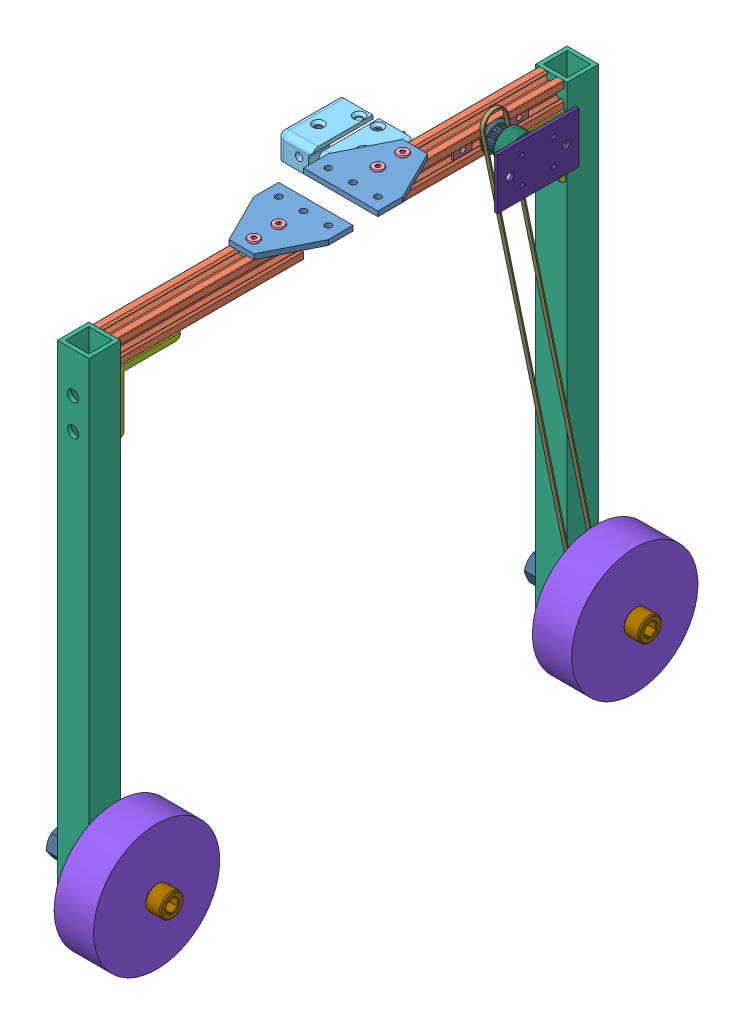
SolidWorks assembly FRP Leg SubAssembly, configuration Default. Lengths in mm.
Overall size (138.8 429.85 487).
31 component instances, 17 part files, 49 mates.
Components (placement in the parent):
- Joining Plate T-1: Joining Plate T [Default] at origin size (60 4 60)
- V-Slot 20x20x150Linear Rail-1: V-Slot 20x20x150Linear Rail [Default] at (0 -10 -160) size (20 20 150)
- Double Tee Nut-1: Double Tee Nut [Default] at (5 -3.4 -11.56) x (0 0 -1) z (0 1 0) size (36.88 10 3)
- Low Profile Screw M5-1: Low Profile Screw M5 [M5 x 8] at (0 -4 -20) x (0 -1 0) z (0 0 1) size (9.62 9 9)
- Low Profile Screw M5-2: Low Profile Screw M5 [M5 x 8] at (0 -4 -40) x (0 -1 0) z (-0.926384 0 0.37658) size (9.62 9 9)
- Low Profile Screw M5-8: Low Profile Screw M5 [M5 x 8] at (0 -4 80) x (0 -1 0) z (0.926384 0 0.37658) size (9.62 9 9)
- Low Profile Screw M5-10: Low Profile Screw M5 [M5 x 8] at (0 -4 60) x (0 -1 0) z (0 0 1) size (9.62 9 9)
- V-Slot 20x20x150Linear Rail-4: V-Slot 20x20x150Linear Rail [Default] at (0 -10 50) size (20 20 150)
- Joining Plate T-4: Joining Plate T [Default] at (0 0 40) x (-1 0 0) z (0 0 -1) size (60 4 60)
- Double Tee Nut-3: Double Tee Nut [Default] at (5 -3.4 88.44) x (0 0 -1) z (0 1 0) size (36.88 10 3)
- Limit Switch Mount_Larger-1: Limit Switch Mount_Larger [Default] at (-28 -8 -42) x (0 0 -1) z (1 0 0) size (56 20 61.19)
- FRP Leg-1: FRP Leg [Default] at (-0.25 -381 -172.7) x (0 0 -1) z (1 0 0) size (25.4 381 25.4)
- L-bracket 20x20-1: L-bracket 20x20 [Default] at (11 -20 -160) x (0 -1 0) z (-1 0 0) size (50 50 22.5)
- Plastic Wheel-1: Plastic Wheel [Default] at (22.61 -361 -172.7) x (0 0 -1) z (1 0 0) size (101.6 101.6 31.75)
- .5in_NYLON SOCKET HEAD CAP SCREW-2: .5in_NYLON SOCKET HEAD CAP SCREW [95868A439] at (-21.84 -361 -172.7) x (0 -0.037736 0.999288) z (-1 0 0) size (19.05 19.05 91.16)
- 94812A620_NYLON 6-6 HEX NUT-1: 94812A620_NYLON 6-6 HEX NUT [94812A620] at (-18.8873 -361 -172.7) x (0 0.381849 -0.924225) z (0 -0.924225 -0.381849) size (19.45 12.65 22.46)
- 1254N220_MXL SERIES LIGHTWEIGHT TIMING BELT PULLEY - Modified-1: 1254N220_MXL SERIES LIGHTWEIGHT TIMING BELT PULLEY - Modified [1254N22] at (13.8724 -361 -172.7) size (11.13 22.35 22.35)
- Pulley-1: Pulley [Default] at (18.6034 -361 -172.7) x (0 -0.202541 0.979274) z (-1 0 0) size (20 395 3.17)
- Tee Nut-12: Tee Nut [Default] at (6.6 -9.5 -103.0192) x (0 0 -1) z (1 0 0) size (15 10 3)
- 1254N220_MXL SERIES LIGHTWEIGHT TIMING BELT PULLEY-3: 1254N220_MXL SERIES LIGHTWEIGHT TIMING BELT PULLEY [1254N22] at (19.7376 -9.5 -103.0192) x (-1 0 0) z (0 -0.692344 -0.721567) size (17.48 22.35 22.35)
- Low Profile Screw M5-11: Low Profile Screw M5 [M5 x 25] at (3.9 -9.5 -103.0192) x (-1 0 0) z (0 -0.155719 -0.987801) size (26.62 9 9)
- Encoder Magnet Mount-1: Encoder Magnet Mount [Default] at (30.6252 -9.5 -103.0192) x (0 0 1) z (-1 0 0) size (24 24 11.5)
- Encoder Board-1: Encoder Board [Default] at (41.6252 -9.5 -103.0192) x (0 0 -1) z (1 0 0) size (31.5 27 3.1)
- Encoder Board Mount-1: Encoder Board Mount [Default] at (46.1252 -9.5 -103.0192) x (0 0 1) z (-1 0 0) size (65.5 41 2.5)
- Tee Nut-13: Tee Nut [Default] at (8.2 -9.5 -125.7692) x (0 0 -1) z (-1 0 0) size (15 10 3)
- Tee Nut-14: Tee Nut [Default] at (8.2 -9.5 -80.2692) x (0 0 -1) z (-1 0 0) size (15 10 3)
- FRP Leg-2: FRP Leg [Default] at (-0.25 -381 212.7) x (0 0 1) z (-1 0 0) size (25.4 381 25.4)
- Plastic Wheel-2: Plastic Wheel [Default] at (54.36 -361 212.7) x (0 0 1) z (-1 0 0) size (101.6 101.6 31.75)
- .5in_NYLON SOCKET HEAD CAP SCREW-3: .5in_NYLON SOCKET HEAD CAP SCREW [95868A439] at (-21.84 -361 212.7) x (0 0.037736 0.999288) z (-1 0 0) size (19.05 19.05 91.16)
- 94812A620_NYLON 6-6 HEX NUT-2: 94812A620_NYLON 6-6 HEX NUT [94812A620] at (-18.8873 -361 212.7) x (0 -0.381849 -0.924225) z (0 -0.924225 0.381849) size (19.45 12.65 22.46)
- L-bracket 20x20-2: L-bracket 20x20 [Default] at (-11.5 -20 200) x (0 -1 0) z (1 0 0) size (50 50 22.5)
Mates (geometry in assembly coordinates):
- Coincident1: coincident anti-aligned: plane of Joining Plate T-1 through (0 0 0) normal (0 -1 0); plane of V-Slot 20x20x150Linear Rail-1 through (0 0 -10) normal (0 1 0)
- Coincident2: coincident: point of Joining Plate T-1; plane of V-Slot 20x20x150Linear Rail-1 through (10 -10 -10) normal (1 0 0)
- Distance1: distance = 20 mm aligned: plane of Joining Plate T-1 through (30 4 10) normal (0 0 1); plane of V-Slot 20x20x150Linear Rail-1 through (0 -10 -10) normal (0 0 1)
- Coincident36: coincident anti-aligned: plane of V-Slot 20x20x150Linear Rail-1 through (0 -1.8 -10) normal (0 -1 0); plane of Double Tee Nut-1 through (-3.5 -1.8 -46.94) normal (0 1 0)
- Concentric11: concentric anti-aligned: cylinder of Joining Plate T-1 through (0 4 -20) axis (0 -1 0) radius 2.55; cylinder of Double Tee Nut-1 through (0 -0.4 -20) axis (0 1 0) radius 2.1
- Concentric12: concentric anti-aligned: cylinder of Joining Plate T-1 through (0 4 -40) axis (0 -1 0) radius 2.55; cylinder of Double Tee Nut-1 through (0 -0.4 -40) axis (0 1 0) radius 2.1
- Coincident49: coincident anti-aligned: plane of Joining Plate T-1 through (0 4 0) normal (0 1 0); plane of Low Profile Screw M5-1 through (4.1614 4 -20) normal (0 -1 0)
- Concentric22: concentric aligned: cylinder of Joining Plate T-1 through (0 4 -20) axis (0 -1 0) radius 2.55; cylinder of Low Profile Screw M5-1 through (0 4 -20) axis (0 -1 0) radius 2.5
- Concentric23: concentric aligned: cylinder of Joining Plate T-1 through (0 4 -40) axis (0 -1 0) radius 2.55; cylinder of Low Profile Screw M5-2 through (0 4 -40) axis (0 -1 0) radius 2.5
- Concentric24: concentric aligned: cylinder of Joining Plate T-1 through (0 4 -40) axis (0 -1 0) radius 2.55; cylinder of Low Profile Screw M5-2 through (0 4 -40) axis (0 -1 0) radius 2.5
- Coincident50: coincident anti-aligned: plane of Joining Plate T-1 through (0 4 0) normal (0 1 0); plane of Low Profile Screw M5-2 through (1.5671 4 -36.1449) normal (0 -1 0)
- Coincident54: coincident anti-aligned: plane of V-Slot 20x20x150Linear Rail-1 through (-10 -10 -10) normal (-1 0 0); plane of Limit Switch Mount_Larger-1 through (-10 0 -42) normal (1 0 0)
- Coincident55: coincident aligned: plane of V-Slot 20x20x150Linear Rail-1 through (0 -10 -10) normal (0 0 1); plane of Limit Switch Mount_Larger-1 through (-28 0 -10) normal (0 0 1)
- Coincident57: coincident aligned: plane of V-Slot 20x20x150Linear Rail-1 through (0 0 -10) normal (0 1 0); plane of Limit Switch Mount_Larger-1 through (-28 0 -42) normal (0 1 0)
- Coincident58: coincident aligned: plane of V-Slot 20x20x150Linear Rail-1 through (0 -10 -160) normal (0 0 -1); plane of L-bracket 20x20-1 through (-11.5 -20 -160) normal (0 0 -1)
- Coincident59: coincident anti-aligned: plane of V-Slot 20x20x150Linear Rail-1 through (0 -20 -10) normal (0 -1 0); plane of L-bracket 20x20-1 through (-11.5 -20 -110) normal (0 1 0)
- Distance2: distance = 1 mm aligned: plane of L-bracket 20x20-1 through (11 -20 -160) normal (1 0 0); plane of V-Slot 20x20x150Linear Rail-1 through (10 -10 -10) normal (1 0 0)
- Concentric25: concentric anti-aligned: cylinder of FRP Leg-1 through (-0.25 -32.5 -185.4) axis (0 0 1) radius 4.5392; cylinder of L-bracket 20x20-1 through (-0.25 -32.5 -110) axis (0 0 -1) radius 3.6
- Coincident62: coincident anti-aligned: plane of FRP Leg-1 through (-12.95 0 -160) normal (0 0 1); plane of L-bracket 20x20-1 through (-11.5 -20 -160) normal (0 0 -1)
- Concentric26: concentric anti-aligned: cylinder of FRP Leg-1 through (-0.25 -57.5 -185.4) axis (0 0 1) radius 4.5392; cylinder of L-bracket 20x20-1 through (-0.25 -57.5 -110) axis (0 0 -1) radius 3.6
- Distance3: distance = 10.16 mm anti-aligned: plane of FRP Leg-1 through (12.45 0 -160) normal (1 0 0); plane of Plastic Wheel-1 through (22.61 -361 -172.7) normal (-1 0 0)
- Concentric32: concentric aligned: cylinder of FRP Leg-1 through (12.45 -361 -172.7) axis (-1 0 0) radius 2.5; cylinder of Plastic Wheel-1 through (54.36 -361 -172.7) axis (-1 0 0) radius 6.35
- Concentric33: concentric aligned: cylinder of Plastic Wheel-1 through (54.36 -361 -172.7) axis (-1 0 0) radius 6.35; cylinder of .5in_NYLON SOCKET HEAD CAP SCREW-2 through (54.36 -361 -172.7) axis (-1 0 0) radius 6.35
- Coincident68: coincident anti-aligned: plane of Plastic Wheel-1 through (54.36 -361 -172.7) normal (1 0 0); plane of .5in_NYLON SOCKET HEAD CAP SCREW-2 through (54.36 -361 -172.7) normal (-1 0 0)
- Coincident69: coincident anti-aligned: plane of FRP Leg-1 through (-12.95 0 -160) normal (-1 0 0); plane of 94812A620_NYLON 6-6 HEX NUT-1 through (-12.95 -361 -172.7) normal (1 0 0)
- Concentric34: concentric anti-aligned: circle of .5in_NYLON SOCKET HEAD CAP SCREW-2; circle of 94812A620_NYLON 6-6 HEX NUT-1
- Coincident70: coincident anti-aligned: plane of Plastic Wheel-1 through (22.61 -361 -172.7) normal (-1 0 0); plane of 1254N220_MXL SERIES LIGHTWEIGHT TIMING BELT PULLEY - Modified-1 through (22.61 -372.176 -172.7) normal (1 0 0)
- Concentric36: concentric aligned: cylinder of .5in_NYLON SOCKET HEAD CAP SCREW-2 through (54.36 -361 -172.7) axis (-1 0 0) radius 6.35; cylinder of 1254N220_MXL SERIES LIGHTWEIGHT TIMING BELT PULLEY - Modified-1 through (22.61 -361 -172.7) axis (-1 0 0) radius 6.35
- Concentric37: concentric anti-aligned: circle of 1254N220_MXL SERIES LIGHTWEIGHT TIMING BELT PULLEY - Modified-1; cylinder of Pulley-1 through (15.4284 -361 -172.7) axis (1 0 0) radius 9
- Distance4: distance = 2 mm anti-aligned: plane of 1254N220_MXL SERIES LIGHTWEIGHT TIMING BELT PULLEY - Modified-1 through (20.6034 -370.0551 -172.7) normal (-1 0 0); plane of Pulley-1 through (18.6034 -361 -172.7) normal (1 0 0)
- Coincident74: coincident anti-aligned: plane of V-Slot 20x20x150Linear Rail-1 through (8.2 -10 -10) normal (-1 0 0); plane of Tee Nut-12 through (8.2 -6.5 -109.0192) normal (1 0 0)
- Coincident75: coincident anti-aligned: plane of V-Slot 20x20x150Linear Rail-1 through (0 -4.5 -10) normal (0 -1 0); plane of Tee Nut-12 through (8.2 -4.5 -100.0192) normal (0 1 0)
- Concentric40: concentric aligned: cylinder of Tee Nut-12 through (9.6 -9.5 -103.0192) axis (1 0 0) radius 2.1; cylinder of 1254N220_MXL SERIES LIGHTWEIGHT TIMING BELT PULLEY-3 through (28.4752 -9.5 -103.0192) axis (1 0 0) radius 3.175
- Concentric41: concentric anti-aligned: cylinder of 1254N220_MXL SERIES LIGHTWEIGHT TIMING BELT PULLEY-3 through (28.4752 -9.5 -103.0192) axis (1 0 0) radius 3.175; cylinder of Low Profile Screw M5-11 through (28.9 -9.5 -103.0192) axis (-1 0 0) radius 2.5
- Coincident76: coincident anti-aligned: plane of V-Slot 20x20x150Linear Rail-1 through (3.9 -10 -10) normal (1 0 0); plane of Low Profile Screw M5-11 through (3.9 -9.5 -103.0192) normal (-1 0 0)
- Distance5: distance = 1 mm anti-aligned: plane of 1254N220_MXL SERIES LIGHTWEIGHT TIMING BELT PULLEY-3 through (11 -17.5642 -95.2815) normal (-1 0 0); plane of V-Slot 20x20x150Linear Rail-1 through (10 -10 -10) normal (1 0 0)
- Coincident78: coincident anti-aligned: plane of 1254N220_MXL SERIES LIGHTWEIGHT TIMING BELT PULLEY-3 through (22.1252 -17.5642 -95.2815) normal (1 0 0); plane of Encoder Magnet Mount-1 through (22.1252 -9.5 -103.0192) normal (-1 0 0)
- Concentric42: concentric aligned: cylinder of 1254N220_MXL SERIES LIGHTWEIGHT TIMING BELT PULLEY-3 through (28.4752 -9.5 -103.0192) axis (1 0 0) radius 8.7376; cylinder of Encoder Magnet Mount-1 through (22.1252 -9.5 -103.0192) axis (1 0 0) radius 12
- Distance6: distance = 10 mm anti-aligned: plane of Encoder Board Mount-1 through (43.6252 -9.5 -103.0192) normal (-1 0 0); plane of Encoder Magnet Mount-1 through (33.6252 -9.5 -103.0192) normal (1 0 0)
- Coincident80: coincident anti-aligned: plane of Encoder Board-1 through (43.6252 -9.5 -103.0192) normal (1 0 0); plane of Encoder Board Mount-1 through (43.6252 -9.5 -103.0192) normal (-1 0 0)
- Concentric43: concentric anti-aligned: cylinder of Encoder Board-1 through (43.6252 1 -115.7692) axis (-1 0 0) radius 1.5625; cylinder of Encoder Board Mount-1 through (43.6252 1 -115.7692) axis (1 0 0) radius 1.75
- Concentric44: concentric anti-aligned: cylinder of Encoder Board-1 through (43.6252 -20 -90.2692) axis (-1 0 0) radius 1.5625; cylinder of Encoder Board Mount-1 through (43.6252 -20 -90.2692) axis (1 0 0) radius 1.75
- Coincident81: coincident anti-aligned: plane of V-Slot 20x20x150Linear Rail-1 through (8.2 -10 -10) normal (-1 0 0); plane of Tee Nut-14 through (8.2 -12.5 -86.2692) normal (1 0 0)
- Coincident82: coincident anti-aligned: plane of V-Slot 20x20x150Linear Rail-1 through (8.2 -10 -10) normal (-1 0 0); plane of Tee Nut-13 through (8.2 -12.5 -131.7692) normal (1 0 0)
- Coincident83: coincident anti-aligned: plane of V-Slot 20x20x150Linear Rail-1 through (0 -4.5 -10) normal (0 -1 0); plane of Tee Nut-13 through (6.6 -4.5 -122.7692) normal (0 1 0)
- Coincident84: coincident anti-aligned: plane of V-Slot 20x20x150Linear Rail-1 through (0 -4.5 -10) normal (0 -1 0); plane of Tee Nut-14 through (6.6 -4.5 -77.2692) normal (0 1 0)
- Concentric45: concentric anti-aligned: cylinder of Encoder Board Mount-1 through (43.6252 -9.5 -80.2692) axis (1 0 0) radius 3; cylinder of Tee Nut-14 through (5.2 -9.5 -80.2692) axis (-1 0 0) radius 2.1
- Concentric46: concentric anti-aligned: cylinder of Encoder Board Mount-1 through (43.6252 -9.5 -125.7692) axis (1 0 0) radius 3; cylinder of Tee Nut-13 through (5.2 -9.5 -125.7692) axis (-1 0 0) radius 2.1
- Concentric47: concentric aligned: cylinder of Encoder Magnet Mount-1 through (22.1252 -9.5 -103.0192) axis (1 0 0) radius 12; cylinder of Encoder Board-1 through (40.5252 -9.5 -103.0192) axis (1 0 0) radius 1.0034
